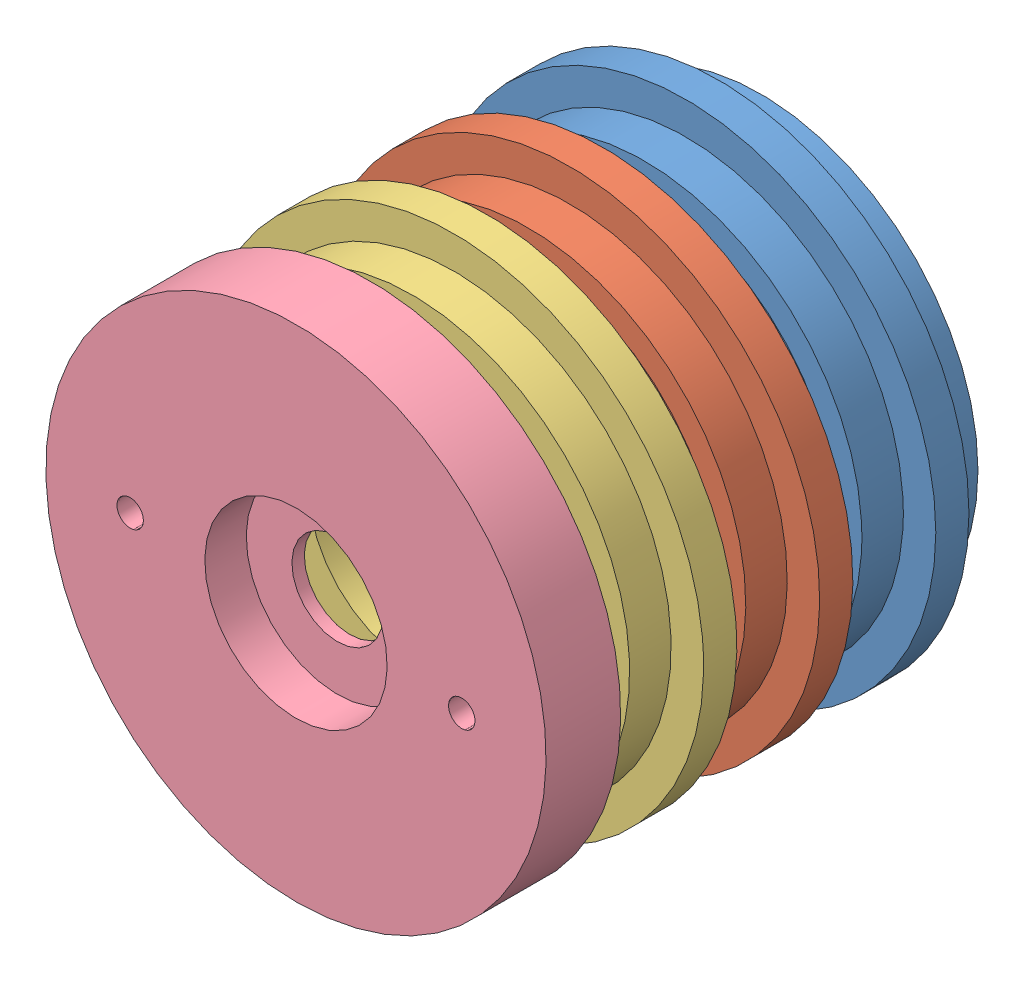
SolidWorks assembly EnsamblajeSeccionesBarra, configuration Predeterminado. Lengths in mm.
Overall size (62.75 62.75 56).
4 component instances, 4 part files, 6 mates.
Components (placement in the parent):
- BridaMotor-1: BridaMotor [Predeterminado] at origin size (60.33 60.33 14)
- TapaMotor-1: TapaMotor [Predeterminado] at (0 0 14) x (0.999929 -0.011904 0) z (0 0 1) size (60.33 60.33 9)
- TapaBridaGB-1: TapaBridaGB [Default] at (0 0 26) x (0.999161 0.040944 0) z (0 0 1) size (60.33 60.33 9)
- BridaGB-1: BridaGB [Predeterminado] at (0 0 44.5) x (0.999726 -0.023405 0) z (0 0 1) size (60.33 60.33 9)
Mates (geometry in assembly coordinates):
- Concéntrica1: concentric aligned: cylinder of BridaMotor-1 through (0 0 -2) axis (0 0 1) radius 30.165; cylinder of TapaMotor-1 through (0 0 12) axis (0 0 1) radius 30.165
- Concéntrica2: concentric anti-aligned: cylinder of TapaMotor-1 through (0 0 12) axis (0 0 1) radius 30.165; cylinder of TapaBridaGB-1 through (0 0 30) axis (0 0 -1) radius 30.165
- Concéntrica3: concentric anti-aligned: cylinder of TapaBridaGB-1 through (0 0 30) axis (0 0 -1) radius 30.165; cylinder of BridaGB-1 through (0 0 38.175) axis (0 0 1) radius 30.165
- Distancia1: distance = 5 mm anti-aligned: plane of TapaMotor-1 through (0 0 12) normal (0 0 -1); plane of BridaMotor-1 through (0 0 7) normal (0 0 1)
- Distancia2: distance = 5 mm anti-aligned: plane of TapaMotor-1 through (0 0 21) normal (0 0 1); plane of TapaBridaGB-1 through (0 0 26) normal (0 0 -1)
- Distancia3: distance = 5 mm anti-aligned: plane of TapaBridaGB-1 through (0 0 35) normal (0 0 1); plane of BridaGB-1 through (0 0 40) normal (0 0 -1)
